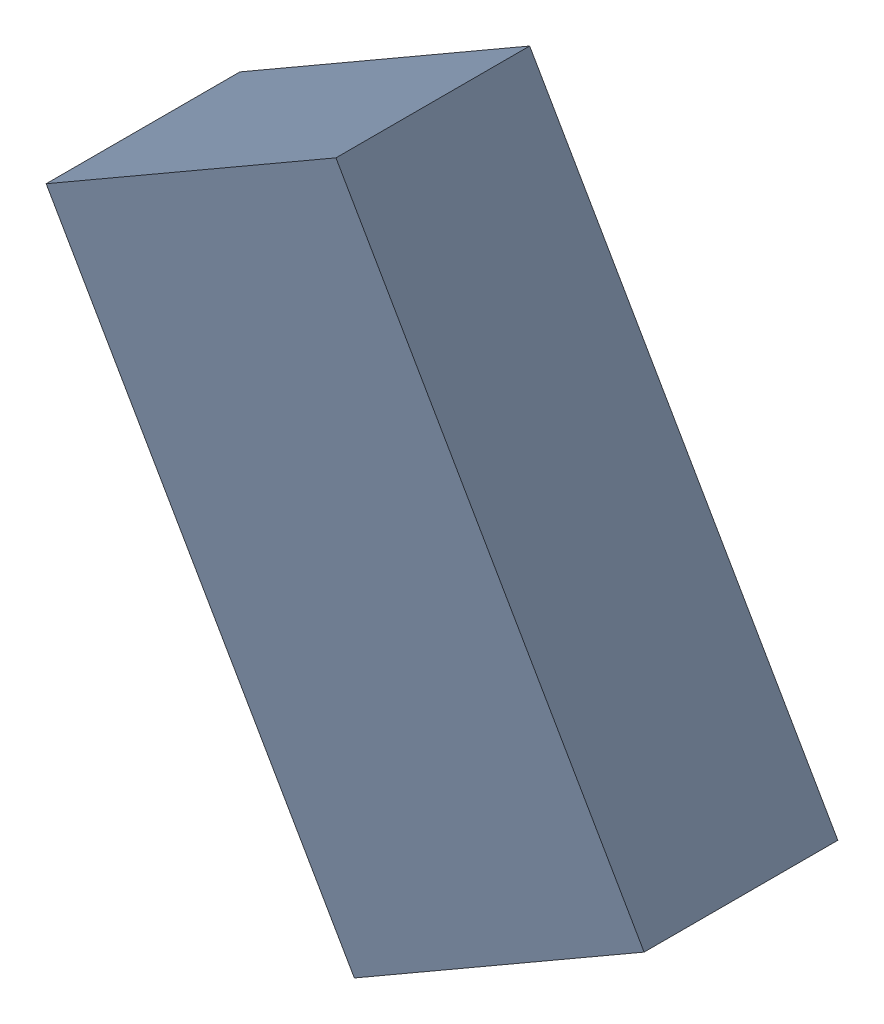
SolidWorks assembly L4_TDA2, configuration Standard. Lengths in mm.
Overall size (1.7 1.99 0.55).
2 component instances, 1 part files, 0 mates.
Components (placement in the parent):
- 885543464-1: 885543464 [Standard] at (49.8001 31.9389 0) size (1.7 1.99 0.55)
  - Extruded_18-1: Extruded_18 [Standard] at origin size (1.7 1.99 0.55)
